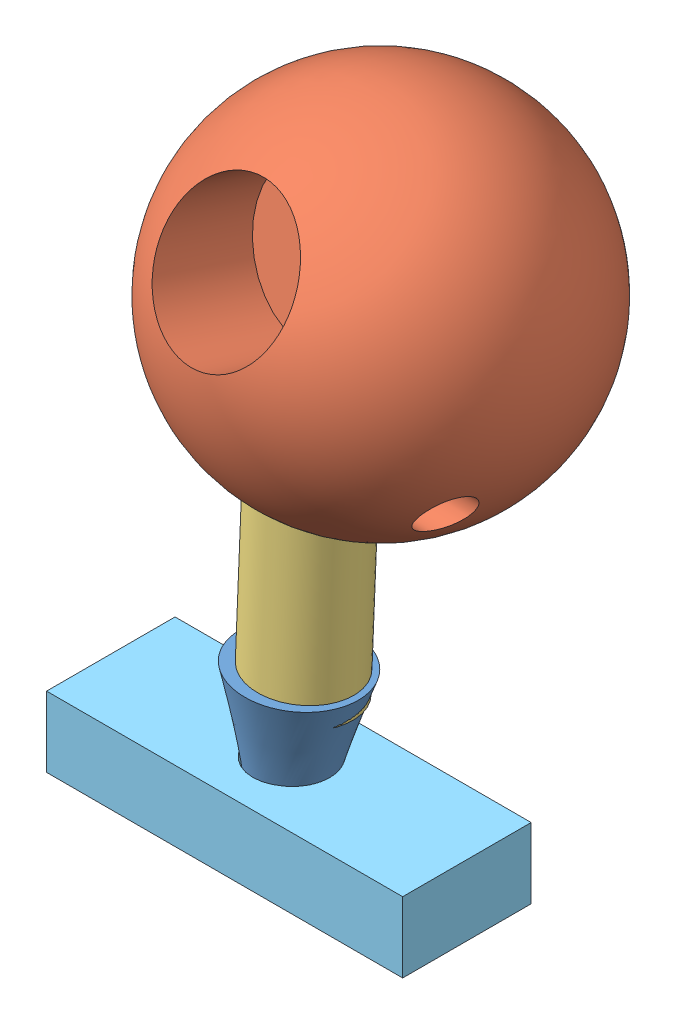
SolidWorks assembly Assem2, configuration Default. Lengths in mm.
Overall size (498.89 387.57 293.96).
28 component instances, 8 part files, 0 mates.
Components (placement in the parent):
- cone-1: cone [Default] at (-268.354 1.6828 176.9691) x (0.993038 -0.052976 -0.105209) z (-0.107189 -0.036025 -0.993586) size (67.9 50 68.97)
- head-1: head [Default] at (-263.5875 165.5589 135.3097) x (-0.991928 -0.061081 -0.111121) z (-0.033642 0.971698 -0.233817) size (486.12 200 200)
- neck-1: neck [Default] at (-266.5651 88.1807 172.4355) x (0.094777 0.038847 0.99474) z (0.995492 -0.007236 -0.094566) size (55 152.51 55)
- SR JOINT - SRJ006C-1: SR JOINT - SRJ006C [Default] at (-271.9179 -57.4631 177.9304) x (0.032637 -0.998425 0.045624) z (0.937247 0.014719 -0.348356) size (26.94 25.01 25.01)
- torso-1: torso [Default] at (-271.197 -83.3647 179.9012) size (202.29 40 72.99)
- 4200-1: 4200 [Default] at (-265.4596 123.4701 160.8243) x (-0.670803 0.267334 0.691778) z (-0.391964 -0.919649 -0.024686) size (14 30.03 30.03)
  - 4200_3-1: 4200_3 [Default] at (3.5 -8.0902 -5.8779) size (4.76 4.76 4.76)
  - 4200_3-2: 4200_3 [Default] at (3.5 -3.0902 -9.5106) size (4.76 4.76 4.76)
  - 4200_3-3: 4200_3 [Default] at (3.5 3.0902 -9.5106) size (4.76 4.76 4.76)
  - 4200_3-4: 4200_3 [Default] at (3.5 8.0902 -5.8779) size (4.76 4.76 4.76)
  - 4200_3-5: 4200_3 [Default] at (3.5 10 0) size (4.76 4.76 4.76)
  - 4200_3-6: 4200_3 [Default] at (3.5 8.0902 5.8779) size (4.76 4.76 4.76)
  - 4200_3-7: 4200_3 [Default] at (3.5 3.0902 9.5106) size (4.76 4.76 4.76)
  - 4200_3-8: 4200_3 [Default] at (3.5 -3.0902 9.5106) size (4.76 4.76 4.76)
  - 4200_3-9: 4200_3 [Default] at (3.5 -8.0902 5.8779) size (4.76 4.76 4.76)
  - 4200_3-10: 4200_3 [Default] at (3.5 -10 0) size (4.76 4.76 4.76)
  - 4200_3-11: 4200_3 [Default] at (10.5 -8.0902 -5.8779) size (4.76 4.76 4.76)
  - 4200_3-12: 4200_3 [Default] at (10.5 -3.0902 -9.5106) size (4.76 4.76 4.76)
  - 4200_3-13: 4200_3 [Default] at (10.5 3.0902 -9.5106) size (4.76 4.76 4.76)
  - 4200_3-14: 4200_3 [Default] at (10.5 8.0902 -5.8779) size (4.76 4.76 4.76)
  - 4200_3-15: 4200_3 [Default] at (10.5 10 0) size (4.76 4.76 4.76)
  - 4200_3-16: 4200_3 [Default] at (10.5 8.0902 5.8779) size (4.76 4.76 4.76)
  - 4200_3-17: 4200_3 [Default] at (10.5 3.0902 9.5106) size (4.76 4.76 4.76)
  - 4200_3-18: 4200_3 [Default] at (10.5 -3.0902 9.5106) size (4.76 4.76 4.76)
  - 4200_3-19: 4200_3 [Default] at (10.5 -8.0902 5.8779) size (4.76 4.76 4.76)
  - 4200_3-20: 4200_3 [Default] at (10.5 -10 0) size (4.76 4.76 4.76)
  - 4200_24-1: 4200_24 [Default] at (14 0 0) x (-1 0 0) z (0 0 1) size (14 30.03 30.03)
  - 4200_26-1: 4200_26 [Default] at origin size (14 17 17)
